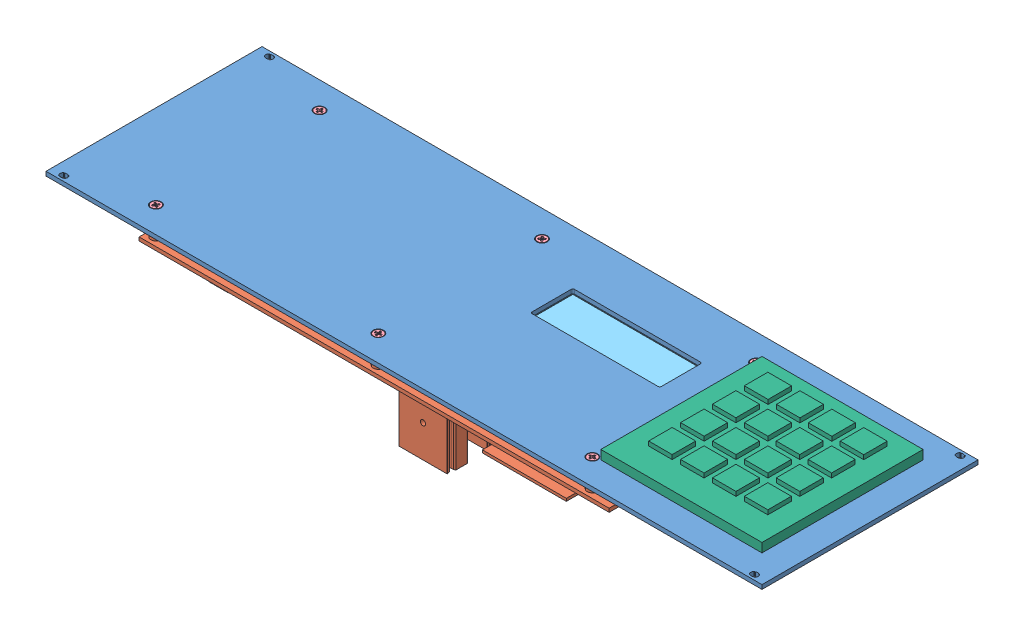
SolidWorks assembly MLA-0387-M0, configuration Default. Lengths in mm.
Overall size (426.52 64.16 128.7).
14 component instances, 6 part files, 28 mates.
Components (placement in the parent):
- MLA-0387-M1-1: MLA-0387-M1 [Default] at (-7.6092 -164.7802 590.2232) size (426.52 2.5 128.7)
- MLA-0387-P0-PA1-1: MLA-0387-P0-PA1 [Default] at (40.1108 198.8099 361.2232) x (1 0 0) z (0 1 0) size (280 107.5 53.66)
- pan_head_phillip_M2x4-1: pan_head_phillip_M2x4 [Default] at (204.3608 203.4199 260.2232) x (1 0 0) z (0 0 1) size (4 9.78 4)
- pan_head_phillip_M2x4-2: pan_head_phillip_M2x4 [Default] at (297.3608 203.4199 260.2232) x (-1 0 0) z (0 0 -1) size (4 9.78 4)
- pan_head_phillip_M2x4-3: pan_head_phillip_M2x4 [Default] at (204.3608 203.4199 315.2232) x (1 0 0) z (0 0 1) size (4 9.78 4)
- pan_head_phillip_M2x4-4: pan_head_phillip_M2x4 [Default] at (297.3608 203.4199 315.2232) x (1 0 0) z (0 0 1) size (4 9.78 4)
- SCREW_ISO 7046-1: SCREW_ISO 7046 [VIJAK M 3x 10] at (45.1108 215.3198 258.7232) x (0 -1 0) z (0 0 1) size (10 5.6 5.6)
- SCREW_ISO 7046-2: SCREW_ISO 7046 [VIJAK M 3x 10] at (45.1108 215.3198 356.2232) x (0 -1 0) z (-0.86006 0 -0.510193) size (10 5.6 5.6)
- SCREW_ISO 7046-3: SCREW_ISO 7046 [VIJAK M 3x 10] at (177.6108 215.2333 356.2232) x (0 -1 0) z (0.989385 0 -0.145321) size (10 5.6 5.6)
- SCREW_ISO 7046-4: SCREW_ISO 7046 [VIJAK M 3x 10] at (177.6108 215.3198 258.7232) x (0 -1 0) z (0.648115 0 0.761542) size (10 5.6 5.6)
- SCREW_ISO 7046-5: SCREW_ISO 7046 [VIJAK M 3x 10] at (305.1108 215.3198 258.7232) x (0 -1 0) z (0 0 1) size (10 5.6 5.6)
- SCREW_ISO 7046-6: SCREW_ISO 7046 [VIJAK M 3x 10] at (305.1108 215.3198 356.2232) x (0 -1 0) z (0 0 1) size (10 5.6 5.6)
- WH2004A1-YYH-3: WH2004A1-YYH [Default] at (201.8608 201.8199 317.7232) x (1 0 0) z (0 1 0) size (98 60 10.6)
- Storm_7016010-4: Storm_7016010 [Default] at (309.2008 215.3198 355.2732) x (1 0 0) z (0 1 0) size (96 96 22)
Mates (geometry in assembly coordinates):
- Concentric32: concentric aligned: cone of MLA-0387-M1-1 through (45.1108 215.3198 258.7232) axis (0 -1 0); cone of SCREW_ISO 7046-1 through (45.1108 213.8198 258.7232) axis (0 -1 0)
- Coincident46: coincident aligned: plane of MLA-0387-M1-1 through (0.4712 215.3198 287.1473) normal (0 1 0); plane of SCREW_ISO 7046-1 through (45.1108 215.3198 258.7232) normal (0 1 0)
- Concentric33: concentric aligned: cone of MLA-0387-M1-1 through (45.1108 215.3198 356.2232) axis (0 -1 0); cone of SCREW_ISO 7046-2 through (45.1108 213.8198 356.2232) axis (0 -1 0)
- Coincident47: coincident aligned: plane of MLA-0387-M1-1 through (0.4712 215.3198 287.1473) normal (0 1 0); plane of SCREW_ISO 7046-2 through (45.1108 215.3198 356.2232) normal (0 1 0)
- Coincident48: coincident: circle of MLA-0387-M1-1; cone of SCREW_ISO 7046-3 through (177.6108 213.7333 356.2232) axis (0 -1 0)
- Concentric34: concentric aligned: cone of MLA-0387-M1-1 through (177.6108 215.3198 258.7232) axis (0 -1 0); cone of SCREW_ISO 7046-4 through (177.6108 213.8198 258.7232) axis (0 -1 0)
- Coincident49: coincident aligned: plane of MLA-0387-M1-1 through (0.4712 215.3198 287.1473) normal (0 1 0); plane of SCREW_ISO 7046-4 through (177.6108 215.3198 258.7232) normal (0 1 0)
- Concentric35: concentric aligned: cone of MLA-0387-M1-1 through (305.1108 215.3198 258.7232) axis (0 -1 0); cone of SCREW_ISO 7046-5 through (305.1108 213.8198 258.7232) axis (0 -1 0)
- Coincident50: coincident aligned: plane of MLA-0387-M1-1 through (0.4712 215.3198 287.1473) normal (0 1 0); plane of SCREW_ISO 7046-5 through (305.1108 215.3198 258.7232) normal (0 1 0)
- Concentric36: concentric aligned: cone of MLA-0387-M1-1 through (305.1108 215.3198 356.2232) axis (0 -1 0); cone of SCREW_ISO 7046-6 through (305.1108 213.8198 356.2232) axis (0 -1 0)
- Coincident51: coincident aligned: plane of MLA-0387-M1-1 through (0.4712 215.3198 287.1473) normal (0 1 0); plane of SCREW_ISO 7046-6 through (305.1108 215.3198 356.2232) normal (0 1 0)
- Coincident60: coincident anti-aligned: plane of MLA-0387-M1-1 through (0.4712 212.8198 287.1473) normal (0 -1 0); plane of MLA-0387-P0-PA1-1 through (177.6108 212.8198 258.7232) normal (0 1 0)
- Concentric37: concentric aligned: cylinder of MLA-0387-M1-1 through (177.6108 215.3198 258.7232) axis (0 -1 0) radius 1.75; cylinder of MLA-0387-P0-PA1-1 through (177.6108 195.2369 258.7232) axis (0 -1 0) radius 1.2295
- Concentric38: concentric aligned: cylinder of MLA-0387-M1-1 through (305.1108 215.3198 356.2232) axis (0 -1 0) radius 1.75; cylinder of MLA-0387-P0-PA1-1 through (305.1108 195.2369 356.2232) axis (0 -1 0) radius 1.2295
- Coincident54: coincident anti-aligned: plane of MLA-0387-P0-PA1-1 through (204.3608 201.8199 260.2232) normal (0 1 0); plane of WH2004A1-YYH-3 through (201.8608 201.8199 317.7232) normal (0 -1 0)
- Concentric39: concentric aligned: cylinder of MLA-0387-P0-PA1-1 through (204.3608 197.4199 260.2232) axis (0 1 0) radius 2.175; cylinder of WH2004A1-YYH-3 through (204.3608 201.8199 260.2232) axis (0 1 0) radius 1.25
- Concentric40: concentric aligned: cylinder of MLA-0387-P0-PA1-1 through (297.3608 197.4199 260.2232) axis (0 1 0) radius 2.175; cylinder of WH2004A1-YYH-3 through (297.3608 201.8199 260.2232) axis (0 1 0) radius 1.25
- Concentric41: concentric anti-aligned: cylinder of pan_head_phillip_M2x4-1 through (204.3608 205.2049 260.2232) axis (0 -1 0) radius 2; cylinder of WH2004A1-YYH-3 through (204.3608 201.8199 260.2232) axis (0 1 0) radius 1.25
- Coincident55: coincident anti-aligned: plane of pan_head_phillip_M2x4-1 through (204.3608 203.4199 260.2232) normal (0 -1 0); plane of WH2004A1-YYH-3 through (201.8608 203.4199 317.7232) normal (0 1 0)
- Concentric42: concentric anti-aligned: cylinder of pan_head_phillip_M2x4-2 through (297.3608 205.2049 260.2232) axis (0 -1 0) radius 2; cylinder of WH2004A1-YYH-3 through (297.3608 201.8199 260.2232) axis (0 1 0) radius 1.25
- Coincident56: coincident anti-aligned: plane of pan_head_phillip_M2x4-2 through (297.3608 203.4199 260.2232) normal (0 -1 0); plane of WH2004A1-YYH-3 through (201.8608 203.4199 317.7232) normal (0 1 0)
- Concentric43: concentric anti-aligned: cylinder of pan_head_phillip_M2x4-4 through (297.3608 205.2049 315.2232) axis (0 -1 0) radius 2; cylinder of WH2004A1-YYH-3 through (297.3608 201.8199 315.2232) axis (0 1 0) radius 1.25
- Coincident57: coincident anti-aligned: plane of pan_head_phillip_M2x4-4 through (297.3608 203.4199 315.2232) normal (0 -1 0); plane of WH2004A1-YYH-3 through (201.8608 203.4199 317.7232) normal (0 1 0)
- Concentric44: concentric aligned: cylinder of pan_head_phillip_M2x4-3 through (204.3608 205.2049 315.2232) axis (0 -1 0) radius 2; circle of WH2004A1-YYH-3
- Coincident58: coincident anti-aligned: plane of pan_head_phillip_M2x4-3 through (204.3608 203.4199 315.2232) normal (0 -1 0); plane of WH2004A1-YYH-3 through (201.8608 203.4199 317.7232) normal (0 1 0)
- Concentric45: concentric anti-aligned: circle of MLA-0387-M1-1; cylinder of Storm_7016010-4 through (389.2008 201.3198 339.2732) axis (0 1 0) radius 1.5
- Concentric46: concentric anti-aligned: circle of MLA-0387-M1-1; cylinder of Storm_7016010-4 through (325.2008 201.3198 275.2732) axis (0 1 0) radius 1.5
- Coincident61: coincident anti-aligned: plane of MLA-0387-M1-1 through (0.4712 215.3198 287.1473) normal (0 1 0); plane of Storm_7016010-4 through (309.2008 215.3198 355.2732) normal (0 -1 0)
